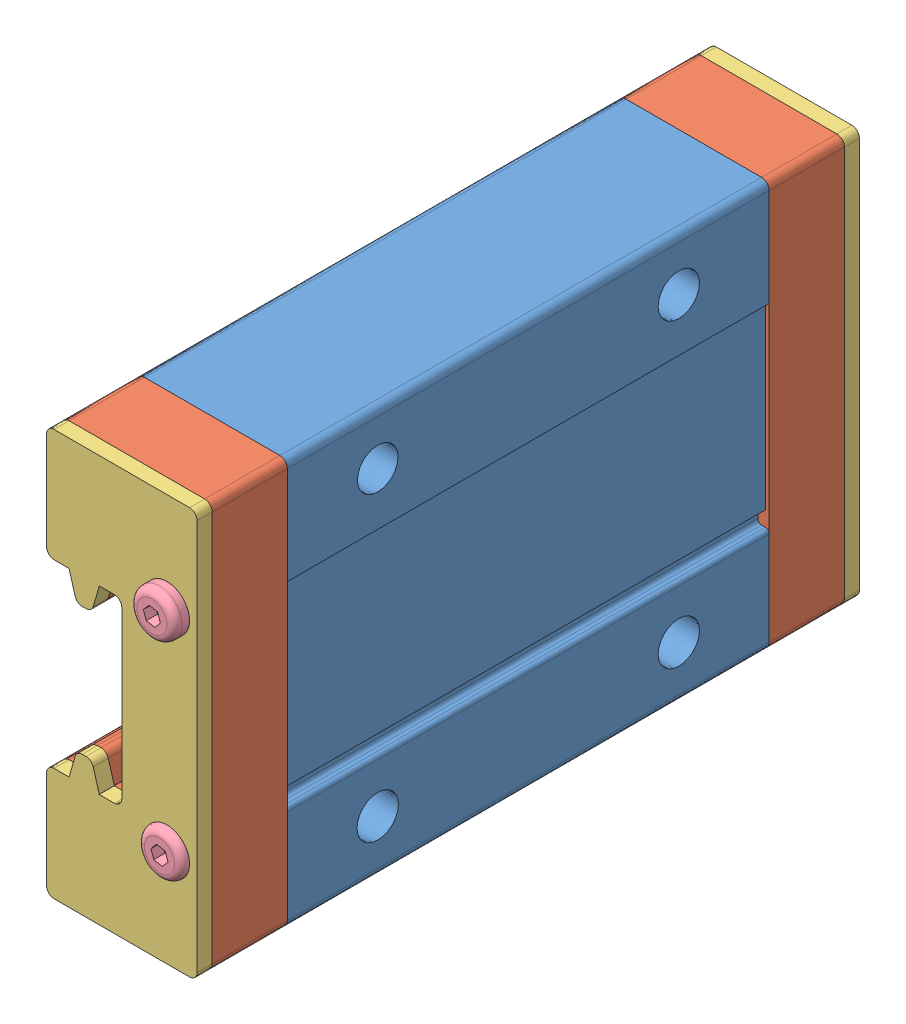
SolidWorks assembly BlockAssem, configuration Default. Lengths in mm.
Overall size (10 27 45.5).
9 component instances, 4 part files, 24 mates.
Components (placement in the parent):
- Main Block-1: Main Block [Default] at (169.1827 226.6144 359.262) x (0 0 1) z (1 0 0) size (32 27 10)
- Green End Cap-1: Green End Cap [Default] at (174.1827 226.6144 343.262) x (0 1 0) z (0 0 -1) size (27 10 5)
- Red End Cap-1: Red End Cap [Default] at (174.1827 226.6144 338.262) x (0 1 0) z (0 0 -1) size (27 10 1)
- Green End Cap-2: Green End Cap [Default] at (174.1827 226.6144 375.262) x (0 -1 0) z (0 0 1) size (27 10 5)
- Red End Cap-2: Red End Cap [Default] at (174.1827 226.6144 380.262) x (0 -1 0) z (0 0 1) size (27 10 1)
- Button M3x8-1: Button M3x8 [Default] at (177.1827 219.6144 381.762) x (0.381849 -0.924225 0) z (0 0 -1) size (3 3 7)
- Button M3x8-2: Button M3x8 [Default] at (177.1827 233.6144 382.262) x (0.381849 -0.924225 0) z (0 0 -1) size (3 3 7)
- Button M3x8-3: Button M3x8 [Default] at (177.1827 219.6144 336.762) x (-0.381849 0.924225 0) z (0 0 1) size (3 3 7)
- Button M3x8-5: Button M3x8 [Default] at (177.1827 233.6144 336.762) x (-0.381849 0.924225 0) z (0 0 1) size (3 3 7)
Mates (geometry in assembly coordinates):
- Coincident1: coincident: plane of ? through (405.2255 225.8015 379.5515) normal (0 0 1); plane of Main Block-1 through (174.1827 220.6144 380.262) normal (-1 0 0)
- Coincident2: coincident: plane of ? through (405.2255 225.8015 379.5515) normal (0 1 0); plane of Main Block-1 through (172.6827 220.6144 380.262) normal (0 1 0)
- Coincident3: coincident anti-aligned: plane of Main Block-1 through (179.1827 213.1144 343.262) normal (0 0 -1); plane of Green End Cap-1 through (174.1827 226.6144 343.262) normal (0 0 1)
- Coincident4: coincident aligned: plane of Main Block-1 through (179.1827 240.1144 343.262) normal (0 1 0); plane of Green End Cap-1 through (179.1827 240.1144 338.262) normal (0 1 0)
- Coincident5: coincident aligned: plane of Main Block-1 through (169.1827 226.6144 359.262) normal (-1 0 0); plane of Green End Cap-1 through (169.1827 232.6144 338.262) normal (-1 0 0)
- Coincident9: coincident anti-aligned: plane of Main Block-1 through (179.1827 213.1144 375.262) normal (0 0 1); plane of Green End Cap-2 through (174.1827 226.6144 375.262) normal (0 0 -1)
- Coincident10: coincident aligned: plane of Main Block-1 through (179.1827 240.1144 343.262) normal (0 1 0); plane of Green End Cap-2 through (179.1827 240.1144 380.262) normal (0 1 0)
- Coincident11: coincident aligned: plane of Main Block-1 through (179.1827 226.6144 359.262) normal (1 0 0); plane of Green End Cap-2 through (179.1827 240.1144 380.262) normal (1 0 0)
- Coincident12: coincident anti-aligned: plane of Green End Cap-2 through (174.1827 226.6144 380.262) normal (0 0 1); plane of Red End Cap-2 through (174.1827 226.6144 380.262) normal (0 0 -1)
- Coincident13: coincident aligned: plane of Green End Cap-2 through (179.1827 240.1144 380.262) normal (0 1 0); plane of Red End Cap-2 through (179.1827 240.1144 381.262) normal (0 1 0)
- Coincident14: coincident aligned: plane of Green End Cap-2 through (179.1827 240.1144 380.262) normal (1 0 0); plane of Red End Cap-2 through (179.1827 240.1144 381.262) normal (1 0 0)
- Coincident16: coincident anti-aligned: plane of Green End Cap-1 through (174.1827 226.6144 338.262) normal (0 0 -1); plane of Red End Cap-1 through (174.1827 226.6144 338.262) normal (0 0 1)
- Coincident17: coincident aligned: plane of Green End Cap-1 through (179.1827 213.1144 338.262) normal (0 -1 0); plane of Red End Cap-1 through (179.1827 213.1144 337.262) normal (0 -1 0)
- Coincident18: coincident aligned: plane of Green End Cap-1 through (169.1827 213.1144 338.262) normal (-1 0 0); plane of Red End Cap-1 through (169.1827 213.1144 337.262) normal (-1 0 0)
- Concentric1: concentric aligned: cylinder of Green End Cap-1 through (177.1827 219.6144 343.262) axis (0 0 -1) radius 1; cylinder of Button M3x8-3 through (177.1827 219.6144 343.762) axis (0 0 -1) radius 1
- Coincident19: coincident anti-aligned: plane of Red End Cap-1 through (177.1827 219.6144 337.762) normal (0 0 -1); plane of Button M3x8-3 through (177.1827 219.6144 337.762) normal (0 0 1)
- Concentric2: concentric aligned: cylinder of Green End Cap-1 through (177.1827 233.6144 343.262) axis (0 0 -1) radius 1; cylinder of Button M3x8-5 through (177.1827 233.6144 343.762) axis (0 0 -1) radius 1
- Coincident20: coincident anti-aligned: plane of Red End Cap-1 through (177.1827 233.6144 337.762) normal (0 0 -1); plane of Button M3x8-5 through (177.1827 233.6144 337.762) normal (0 0 1)
- Concentric3: concentric aligned: cylinder of Green End Cap-2 through (177.1827 219.6144 375.262) axis (0 0 1) radius 1; cylinder of Button M3x8-1 through (177.1827 219.6144 374.762) axis (0 0 1) radius 1
- Coincident21: coincident anti-aligned: plane of Red End Cap-2 through (177.1827 219.6144 380.762) normal (0 0 1); plane of Button M3x8-1 through (177.1827 219.6144 380.762) normal (0 0 -1)
- Concentric4: concentric aligned: cylinder of Green End Cap-2 through (177.1827 233.6144 375.262) axis (0 0 1) radius 1; cylinder of Button M3x8-2 through (177.1827 233.6144 375.262) axis (0 0 1) radius 1
- Coincident22: coincident anti-aligned: plane of Red End Cap-2 through (174.1827 226.6144 381.262) normal (0 0 1); plane of Button M3x8-2 through (177.1827 233.6144 381.262) normal (0 0 -1)
- Coincident24: coincident anti-aligned: plane of Main Block-1 through (174.1827 220.6144 380.262) normal (-1 0 0); plane of ? through (166.1827 232.5585 379.9218) normal (-1 0 0)
- Coincident25: coincident anti-aligned: plane of Main Block-1 through (172.6827 232.6144 380.262) normal (0 -1 0); plane of ? through (166.1827 220.5585 379.9218) normal (0 -1 0)
